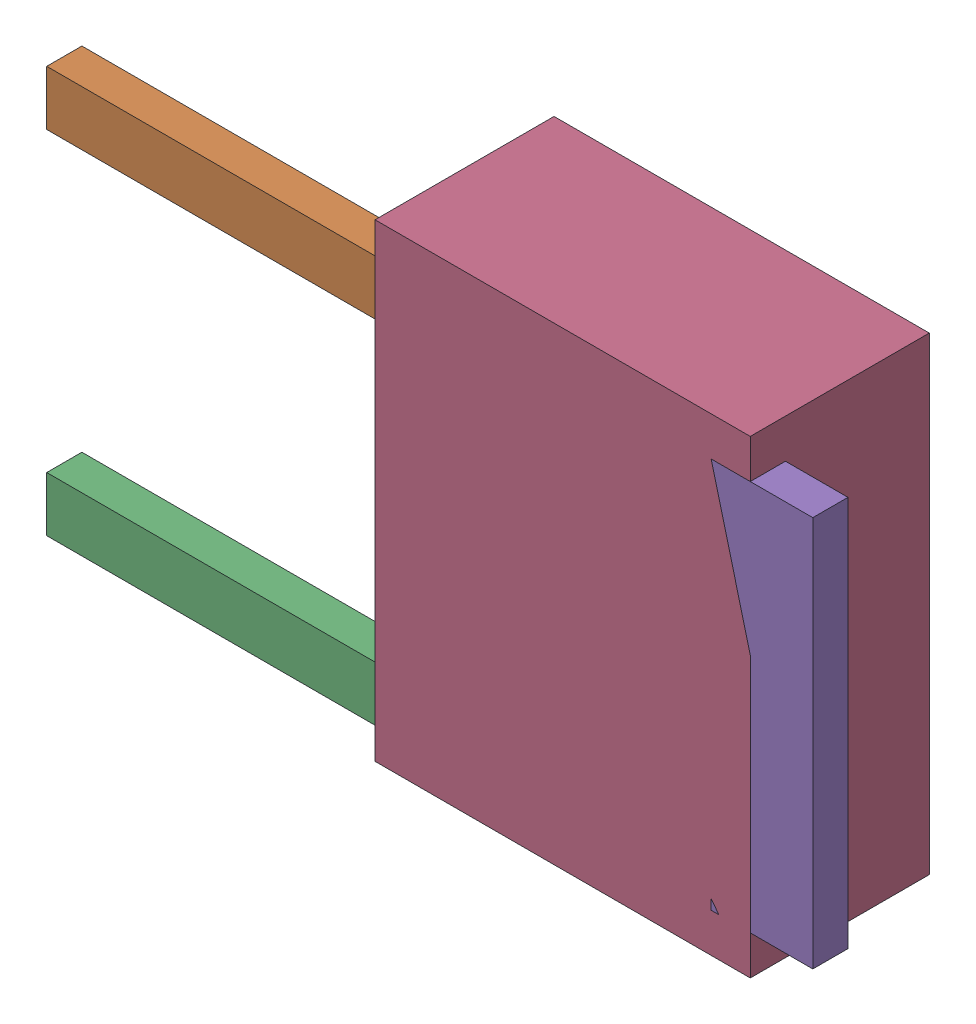
SolidWorks assembly 3.3V_Reg, configuration Default. Lengths in mm.
Overall size (9.8 6 2.29).
10 component instances, 4 part files, 0 mates.
Components (placement in the parent):
- 402661264-1: 402661264 [Default] at (37.4906 76.4532 -2.6824) size (0.7 0.7 0.44)
  - Extruded_33-1: Extruded_33 [Default] at origin size (0.7 0.7 0.44)
- 402661136-1: 402661136 [Default] at (35.5906 78.6532 -1.5524) size (4.3 0.7 0.45)
  - Extruded_34-1: Extruded_34 [Default] at origin size (4.3 0.7 0.45)
- 402661136-2: 402661136 [Default] at (35.5906 74.1532 -1.5524) size (4.3 0.7 0.45)
  - Extruded_34-1: Extruded_34 [Default] at origin size (4.3 0.7 0.45)
- 402661008-1: 402661008 [Default] at (40.0406 76.4032 -3.3924) size (4.8 6 2.29)
  - Extruded_35-1: Extruded_35 [Default] at origin size (4.8 6 2.29)
- 402660880-1: 402660880 [Default] at (42.5906 76.4032 -1.5524) size (1.3 5 0.45)
  - Extruded_36-1: Extruded_36 [Default] at origin size (1.3 5 0.45)
